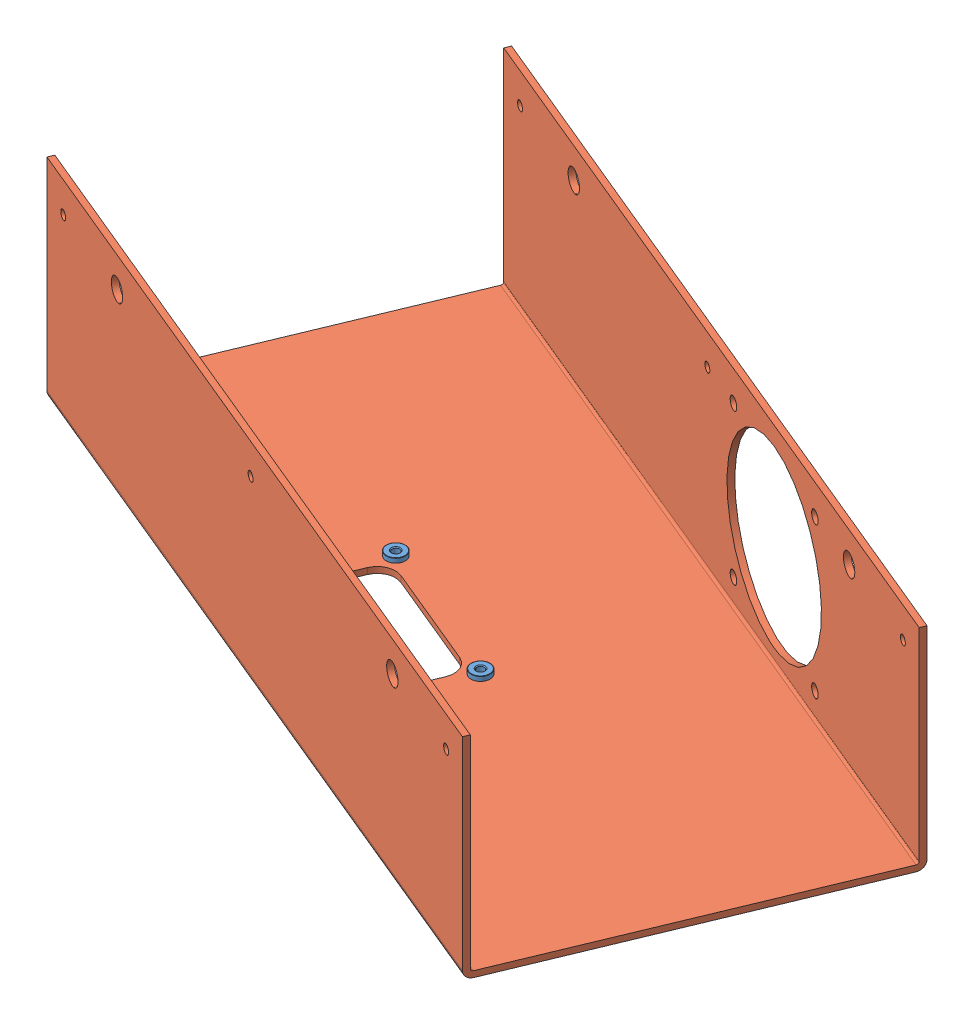
SolidWorks assembly DtacqShell, configuration Default. Lengths in mm.
Overall size (280.75 70 206.68).
5 component instances, 2 part files, 4 mates.
Components (placement in the parent):
- 3503_F-1: 3503_F [Default] at origin size (6.3 2.87 6.3)
- 3503_F-2: 3503_F [Default] at (14.5559 0 -35.1017) size (6.3 2.87 6.3)
- 3503_F-3: 3503_F [Default] at (48.0339 0 19.9185) size (6.3 2.87 6.3)
- 3503_F-4: 3503_F [Default] at (62.5897 0 -15.1831) size (6.3 2.87 6.3)
- UTopFold-1: UTopFold [Default] at (-17.7136 80.87 -119.4015) x (0 1 0) z (0.383049 0 -0.923728) size (70 255 118)
Mates (geometry in assembly coordinates):
- Coincident144: coincident aligned: plane of 3503_F-1 through (3.0201 2.87 0) normal (0 1 0); plane of 3503_F-2 through (17.576 2.87 -35.1017) normal (0 1 0)
- Coincident145: coincident aligned: plane of 3503_F-1 through (3.0201 2.87 0) normal (0 1 0); plane of 3503_F-3 through (51.054 2.87 19.9185) normal (0 1 0)
- Coincident146: coincident aligned: plane of 3503_F-3 through (51.054 2.87 19.9185) normal (0 1 0); plane of 3503_F-4 through (65.6098 2.87 -15.1831) normal (0 1 0)
- Coincident219: coincident anti-aligned: circle of 3503_F-1; plane of UTopFold-1 through (-190.1235 1.37 218.0549) normal (0 1 0)
